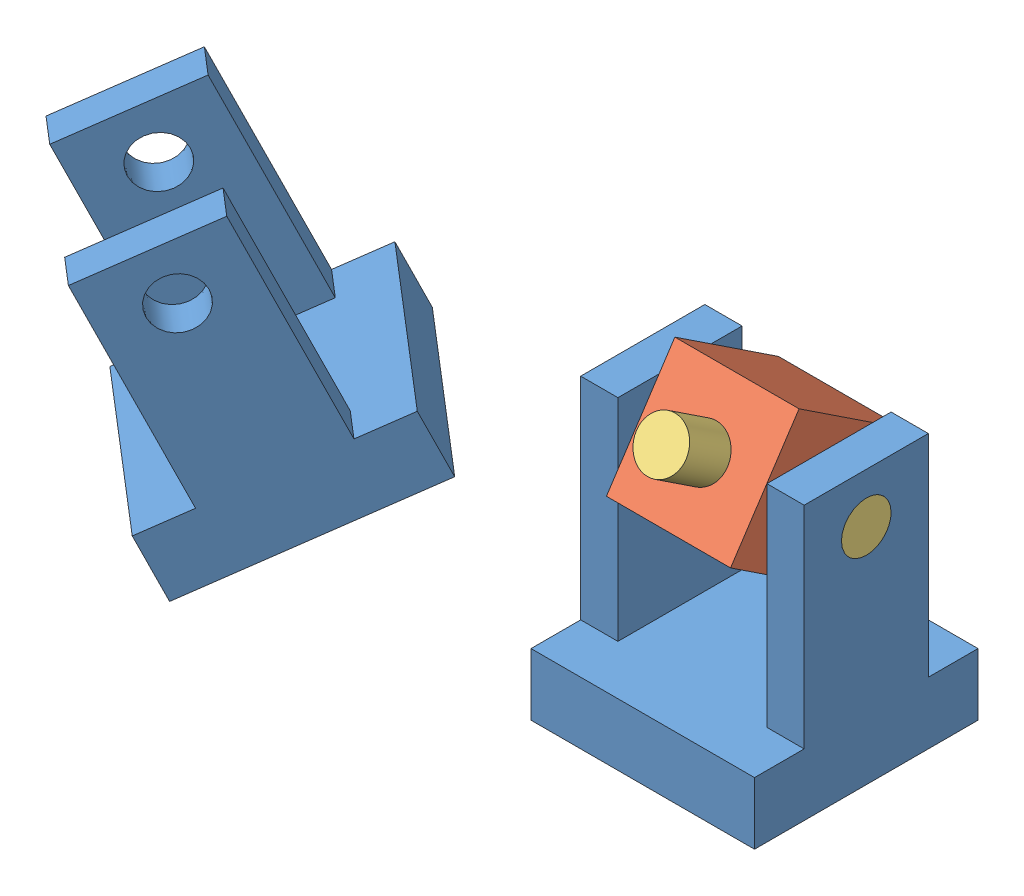
SolidWorks assembly Assem1, configuration Default. Lengths in mm.
Overall size (266.71 177.17 193.01).
7 component instances, 3 part files, 10 mates.
Components (placement in the parent):
- U-Bracket-1: U-Bracket [Default] at (-39.6126 -81.0494 38.6006) size (90 110 90)
- Square Block-1: Square Block [Default] at (-39.6126 8.9506 38.6006) x (1 0 0) z (0 0.551559 0.834136) size (50 50 50)
- Pin-1: Pin [Default] at (-9.6126 8.9506 38.6006) size (30 20 20)
- Pin-2: Pin [Default] at (-69.6126 8.9506 38.6006) size (30 20 20)
- Pin-3: Pin [Default] at (-39.6126 25.4974 63.6247) x (0 -0.551559 -0.834136) z (1 0 0) size (30 20 20)
- Pin-4: Pin [Default] at (-39.6126 -7.5961 13.5765) x (0 -0.551559 -0.834136) z (1 0 0) size (30 20 20)
- U-Bracket-2: U-Bracket [Default] at (-167.1984 -24.5959 93.6498) x (0.75463 0.047725 0.654413) z (-0.578036 -0.423602 0.697449) size (90 110 90)
Mates (geometry in assembly coordinates):
- Coincident1: coincident anti-aligned: plane of Square Block-1 through (-24.6126 8.9506 38.6006) normal (1 0 0); plane of Pin-1 through (-24.6126 8.9506 38.6006) normal (-1 0 0)
- Concentric1: concentric anti-aligned: cylinder of Square Block-1 through (-24.6126 8.9506 38.6006) axis (1 0 0) radius 10; cylinder of Pin-1 through (5.3874 8.9506 38.6006) axis (-1 0 0) radius 10
- Coincident2: coincident anti-aligned: plane of Square Block-1 through (-54.6126 8.9506 38.6006) normal (-1 0 0); plane of Pin-2 through (-54.6126 8.9506 38.6006) normal (1 0 0)
- Concentric2: concentric aligned: cylinder of Square Block-1 through (-54.6126 8.9506 38.6006) axis (-1 0 0) radius 10; cylinder of Pin-2 through (-54.6126 8.9506 38.6006) axis (-1 0 0) radius 10
- Coincident3: coincident anti-aligned: plane of Square Block-1 through (-39.6126 17.224 51.1126) normal (0 0.551559 0.834136); plane of Pin-3 through (-39.6126 17.224 51.1126) normal (0 -0.551559 -0.834136)
- Concentric3: concentric aligned: cylinder of Square Block-1 through (-39.6126 17.224 51.1126) axis (0 0.551559 0.834136) radius 10; cylinder of Pin-3 through (-39.6126 17.224 51.1126) axis (0 0.551559 0.834136) radius 10
- Coincident4: coincident anti-aligned: plane of Square Block-1 through (-39.6126 0.6772 26.0885) normal (0 -0.551559 -0.834136); plane of Pin-4 through (-39.6126 0.6772 26.0885) normal (0 0.551559 0.834136)
- Concentric4: concentric anti-aligned: cylinder of Square Block-1 through (-39.6126 0.6772 26.0885) axis (0 -0.551559 -0.834136) radius 10; cylinder of Pin-4 through (-39.6126 -15.8695 1.0645) axis (0 0.551559 0.834136) radius 10
- Coincident5: coincident aligned: plane of U-Bracket-1 through (5.3874 -81.0494 38.6006) normal (1 0 0); plane of Pin-1 through (5.3874 8.9506 38.6006) normal (1 0 0)
- Concentric5: concentric anti-aligned: cylinder of U-Bracket-1 through (-84.6126 8.9506 38.6006) axis (1 0 0) radius 10; cylinder of Pin-1 through (5.3874 8.9506 38.6006) axis (-1 0 0) radius 10
